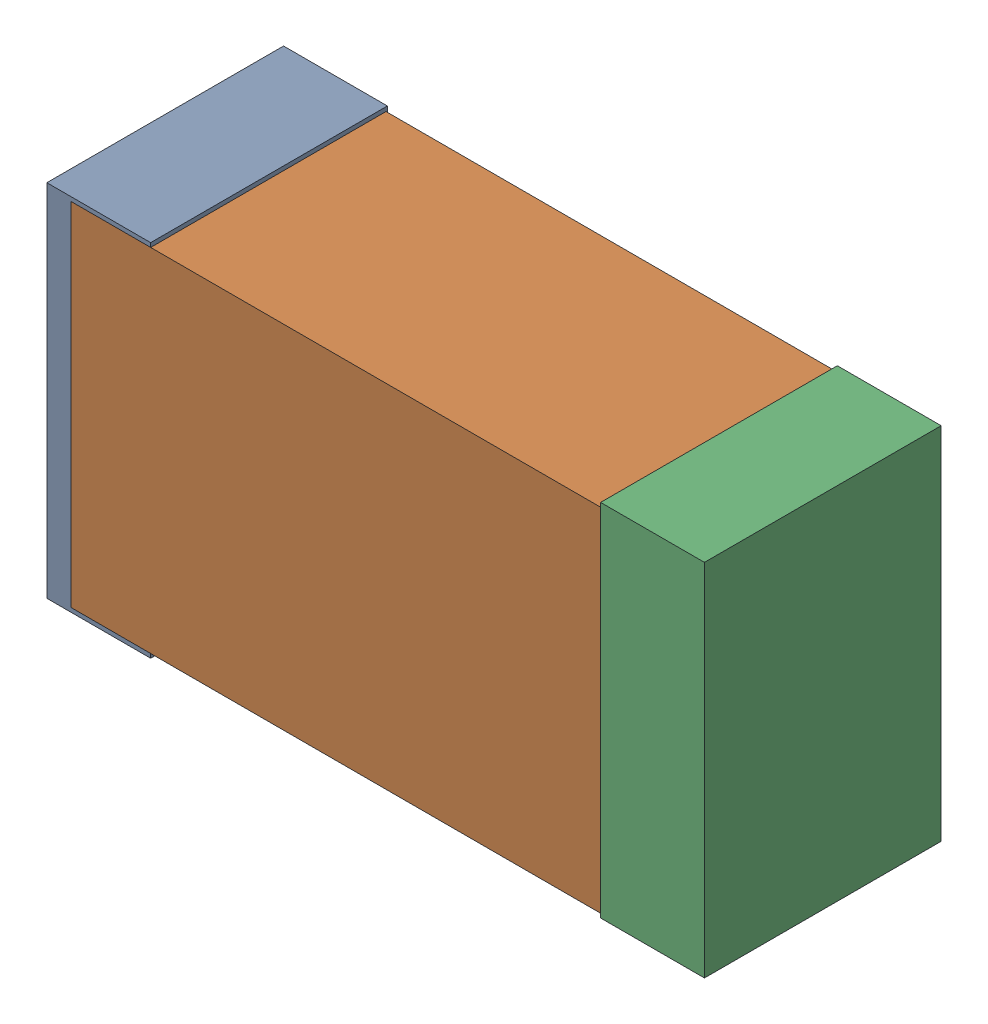
SolidWorks assembly C5Kanaloa_v2.0.0_Motor, configuration Default. Lengths in mm.
Overall size (2.38 1.3 0.85).
6 component instances, 2 part files, 0 mates.
Components (placement in the parent):
- 352877648-1: 352877648 [Default] at (77.994 107.7722 -1.9574) size (0.38 1.3 0.85)
  - Extruded_14-1: Extruded_14 [Default] at origin size (0.38 1.3 0.85)
- 352877904-1: 352877904 [Default] at (78.994 107.7722 -1.9524) size (2.2 1.27 0.85)
  - Extruded_18-1: Extruded_18 [Default] at origin size (2.2 1.27 0.85)
- 352877648-2: 352877648 [Default] at (79.994 107.7722 -1.9574) size (0.38 1.3 0.85)
  - Extruded_14-1: Extruded_14 [Default] at origin size (0.38 1.3 0.85)
